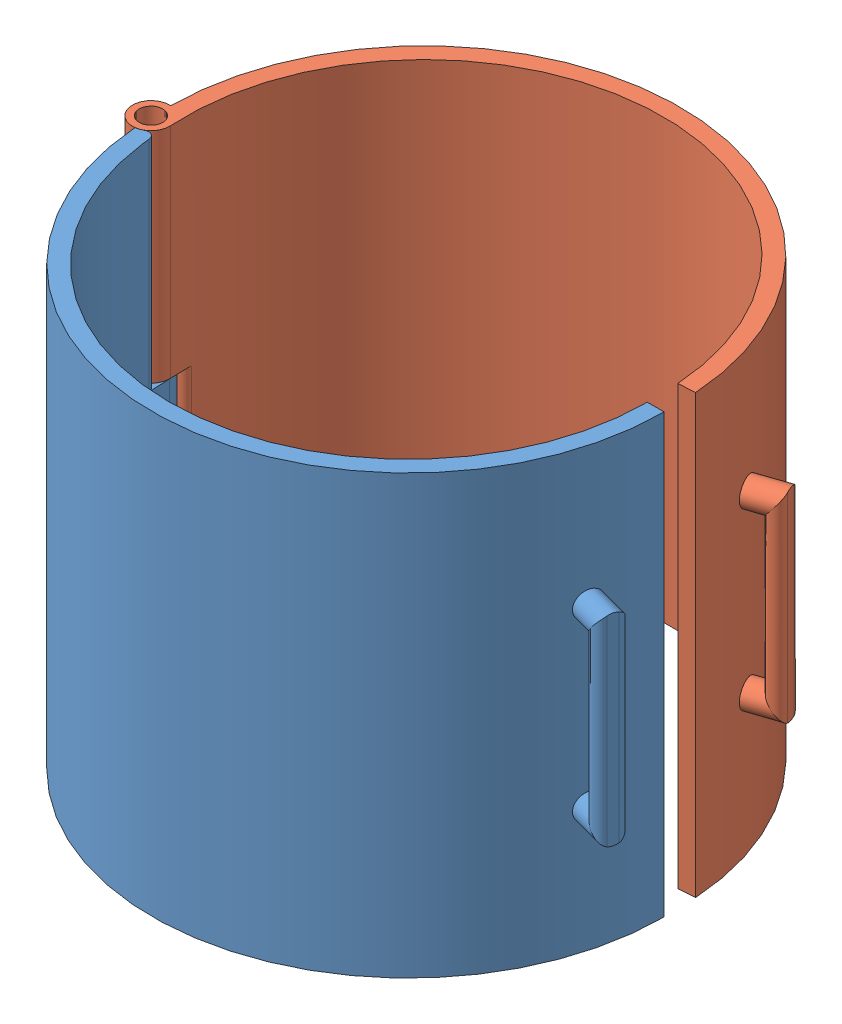
SolidWorks assembly prototype, configuration Default. Lengths in mm.
Overall size (170.38 130 162).
2 component instances, 2 part files, 2 mates.
Components (placement in the parent):
- 1hinge tube right-1: 1hinge tube right [Default] at (-47.0054 -58.1375 -15.5153) size (165.54 130 81.5)
- 1hinge tube left-1: 1hinge tube left [Default] at (-47.1595 71.8625 -20.3688) x (0.997985 0 -0.063443) z (-0.063443 0 -0.997985) size (165.54 130 81.5)
Mates (geometry in assembly coordinates):
- Concentric1: concentric anti-aligned: cylinder of 1hinge tube right-1 through (-123.5054 6.8625 -15.5153) axis (0 -1 0) radius 3.5; cylinder of 1hinge tube left-1 through (-123.5054 6.8625 -15.5153) axis (0 1 0) radius 3.5
- Coincident1: coincident anti-aligned: plane of 1hinge tube right-1 through (-47.0054 6.8625 -15.5153) normal (0 1 0); plane of 1hinge tube left-1 through (-47.1595 6.8625 -20.3688) normal (0 -1 0)
